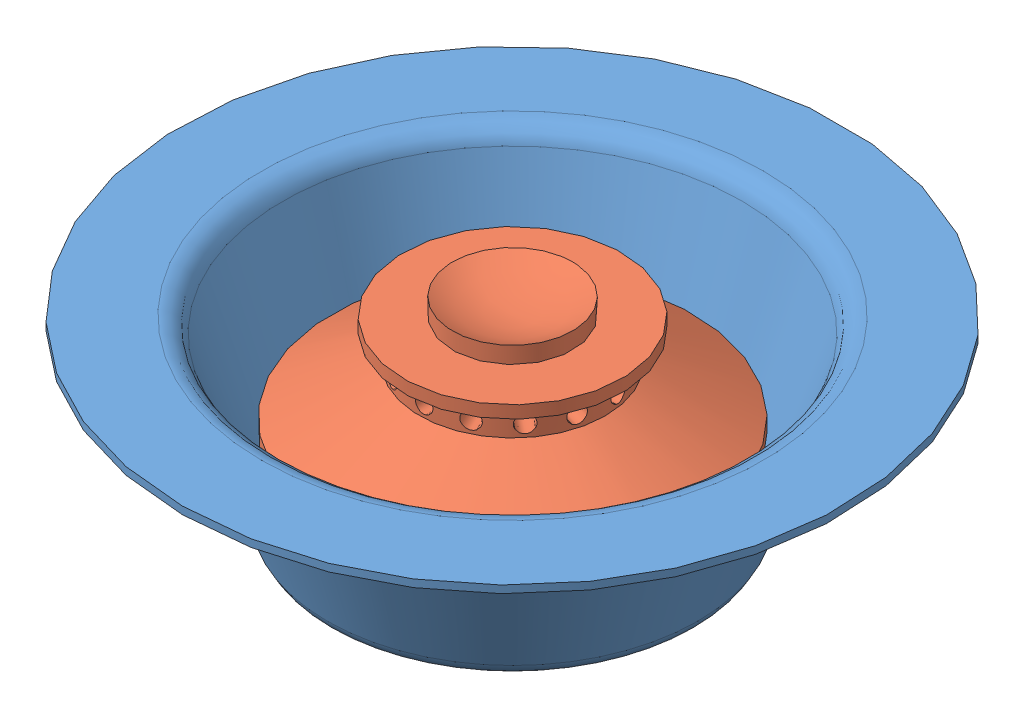
SolidWorks assembly range_burner, configuration Default. Lengths in mm.
Overall size (139.7 50.8 139.7).
2 component instances, 2 part files, 2 mates.
Components (placement in the parent):
- range_burner_bowl-1: range_burner_bowl [Default] at origin
- range_burner_head-1: range_burner_head [Default] at (0 17.8134 0) x (0.999007 0 -0.04455) z (0.04455 0 0.999007)
Mates (geometry in assembly coordinates):
- Concentric1: concentric: cone of range_burner_bowl-1 through (0 3.2565 0) axis (0 -1 0); cylinder of range_burner_head-1 through (0 40.0384 0) axis (0 -1 0) radius 23.1308
- Coincident1: coincident: plane of range_burner_bowl-1 through (-53.0884 39.6875 0) normal (0 1 0); plane of range_burner_head-1 through (-12.6874 39.6875 0.5658) normal (0 1 0)
